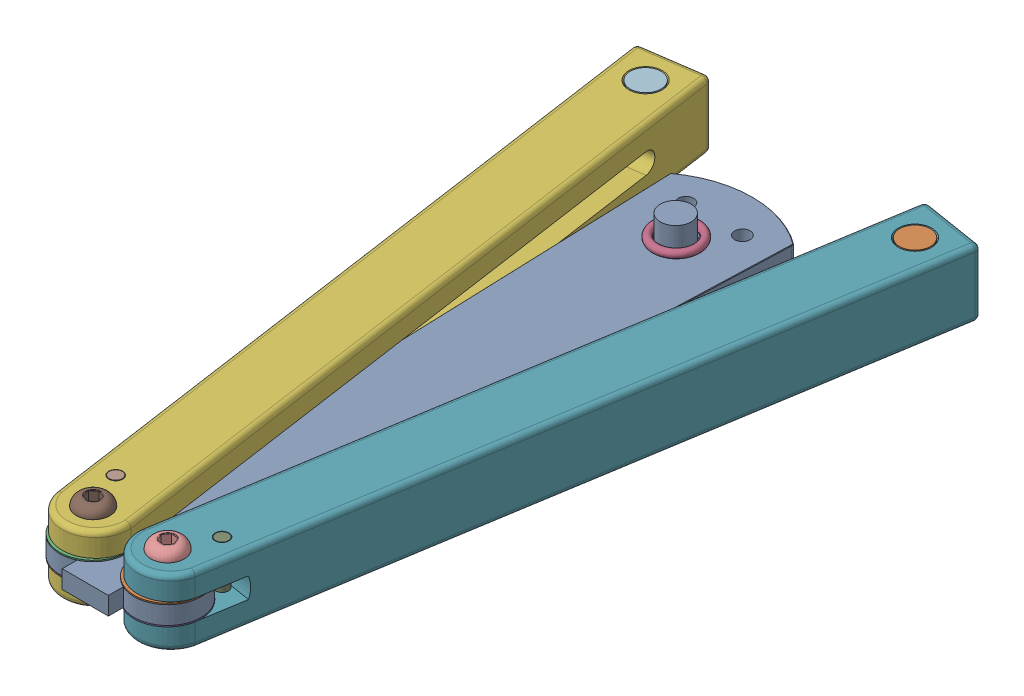
SolidWorks assembly Balisong_full, configuration Default. Lengths in mm.
Overall size (67.65 16.53 142.31).
16 component instances, 7 part files, 22 mates.
Components (placement in the parent):
- Balisong_blade-1: Balisong_blade [Default] at origin size (27.5 3.5 130)
- Balisong_washer-2: Balisong_washer [Default] at (7.25 1.75 121.2169) size (13 0.25 13)
- Balisong_washer-4: Balisong_washer [Default] at (-7.25 1.75 121.2169) size (13 0.25 13)
- Balisong_washer-5: Balisong_washer [Default] at (-7.25 -2 121.2169) size (13 0.25 13)
- Balisong_washer-6: Balisong_washer [Default] at (7.25 -2 121.2169) size (13 0.25 13)
- Balisong_handle-2: Balisong_handle [Default] at (0.7258 0 125.4018) x (-0.109204 0 -0.994019) z (0.994019 0 -0.109204) size (139.54 13.11 17.47)
- Balisong_handle-3: Balisong_handle [Default] at (-0.7953 0 125.2666) x (0.125975 0 -0.992033) z (-0.992033 0 -0.125975) size (139.54 13.11 17.47)
- Balisong_pin-1: Balisong_pin [Default] at (-10.3204 -6.4661 113.7565) x (0.994668 0 -0.103126) z (0.103126 0 0.994668) size (2.5 13 2.5)
- Balisong_pin-2: Balisong_pin [Default] at (10.4459 -6.5095 113.8094) x (0.999524 0 -0.030846) z (0.030846 0 0.999524) size (2.5 13 2.5)
- Balisong_bolt-1: Balisong_bolt [Default] at (7.25 6.5087 121.2169) x (0.115249 0 -0.993337) z (0.993337 0 0.115249) size (6.5 16.5 6.5)
- Balisong_bolt-2: Balisong_bolt [Default] at (-7.25 6.5387 121.2169) x (0.307244 0 -0.951631) z (0.951631 0 0.307244) size (6.5 16.5 6.5)
- Balisong_weight-1: Balisong_weight [Default] at (-25.3413 -6.4895 -4.4879) x (0.714879 0 0.699248) z (-0.699248 0 0.714879) size (6 13 6)
- Balisong_weight-2: Balisong_weight [Default] at (0 -6.4912 15) x (0.953648 0 -0.300924) z (0.300924 0 0.953648) size (6 13 6)
- Balisong_weight-3: Balisong_weight [Default] at (27.4616 -6.4882 -4.1645) x (0.999852 0 0.017188) z (-0.017188 0 0.999852) size (6 13 6)
- Balisong_band-1: Balisong_band [Default] at (0.0787 -2.5695 15.1468) size (9.5 1.5 9.5)
- Balisong_band-2: Balisong_band [Default] at (0.1363 2.5915 15.017) size (9.5 1.5 9.5)
Mates (geometry in assembly coordinates):
- Coincident5: coincident aligned: circle of Balisong_blade-1; circle of Balisong_washer-2
- Coincident6: coincident aligned: circle of Balisong_blade-1; circle of Balisong_washer-4
- Coincident7: coincident aligned: circle of Balisong_blade-1; circle of Balisong_washer-5
- Coincident8: coincident aligned: circle of Balisong_blade-1; circle of Balisong_washer-6
- Coincident9: coincident aligned: circle of Balisong_washer-4; circle of Balisong_handle-2
- Coincident11: coincident anti-aligned: circle of Balisong_washer-2; circle of Balisong_handle-3
- Concentric4: concentric anti-aligned: cylinder of Balisong_handle-2 through (-10.3204 -6.5 113.7565) axis (0 1 0) radius 1.25; cylinder of Balisong_pin-1 through (-10.3204 6.5339 113.7565) axis (0 -1 0) radius 1.25
- Lock2: lock: unknown of Balisong_handle-2; unknown of Balisong_pin-1
- Concentric6: concentric aligned: cylinder of Balisong_pin-2 through (10.4459 6.4905 113.8094) axis (0 -1 0) radius 1.25; cylinder of Balisong_handle-3 through (10.4459 6.5 113.8094) axis (0 -1 0) radius 1.25
- Lock3: lock: unknown of Balisong_handle-3; unknown of Balisong_pin-2
- Concentric7: concentric anti-aligned: cylinder of Balisong_handle-3 through (7.25 6.5 121.2169) axis (0 -1 0) radius 2; cylinder of Balisong_bolt-1 through (7.25 -6.4913 121.2169) axis (0 1 0) radius 2
- Lock4: lock: unknown of Balisong_handle-3; unknown of Balisong_bolt-1
- Concentric9: concentric aligned: cylinder of Balisong_handle-2 through (-7.25 -6.5 121.2169) axis (0 1 0) radius 2; cylinder of Balisong_bolt-2 through (-7.25 -6.4613 121.2169) axis (0 1 0) radius 2
- Lock5: lock: unknown of Balisong_handle-2; unknown of Balisong_bolt-2
- Concentric11: concentric anti-aligned: cylinder of Balisong_handle-2 through (-25.3413 -6.5 -4.4879) axis (0 1 0) radius 3; cylinder of Balisong_weight-1 through (-25.3413 6.5105 -4.4879) axis (0 -1 0) radius 3
- Lock7: lock: unknown of Balisong_handle-2; unknown of Balisong_weight-1
- Concentric13: concentric aligned: cylinder of Balisong_handle-3 through (27.4616 6.5 -4.1645) axis (0 -1 0) radius 3; cylinder of Balisong_weight-3 through (27.4616 6.5118 -4.1645) axis (0 -1 0) radius 3
- Concentric14: concentric anti-aligned: cylinder of Balisong_blade-1 through (0 -1.75 15) axis (0 1 0) radius 3.25; cylinder of Balisong_weight-2 through (0 6.5088 15) axis (0 -1 0) radius 3
- Lock8: lock: unknown of Balisong_handle-3; unknown of Balisong_weight-3
- Lock9: lock: unknown of Balisong_blade-1; unknown of Balisong_weight-2
- Lock13: lock: unknown of Balisong_weight-2; unknown of Balisong_band-2
- Lock14: lock: unknown of Balisong_weight-2; unknown of Balisong_band-1
